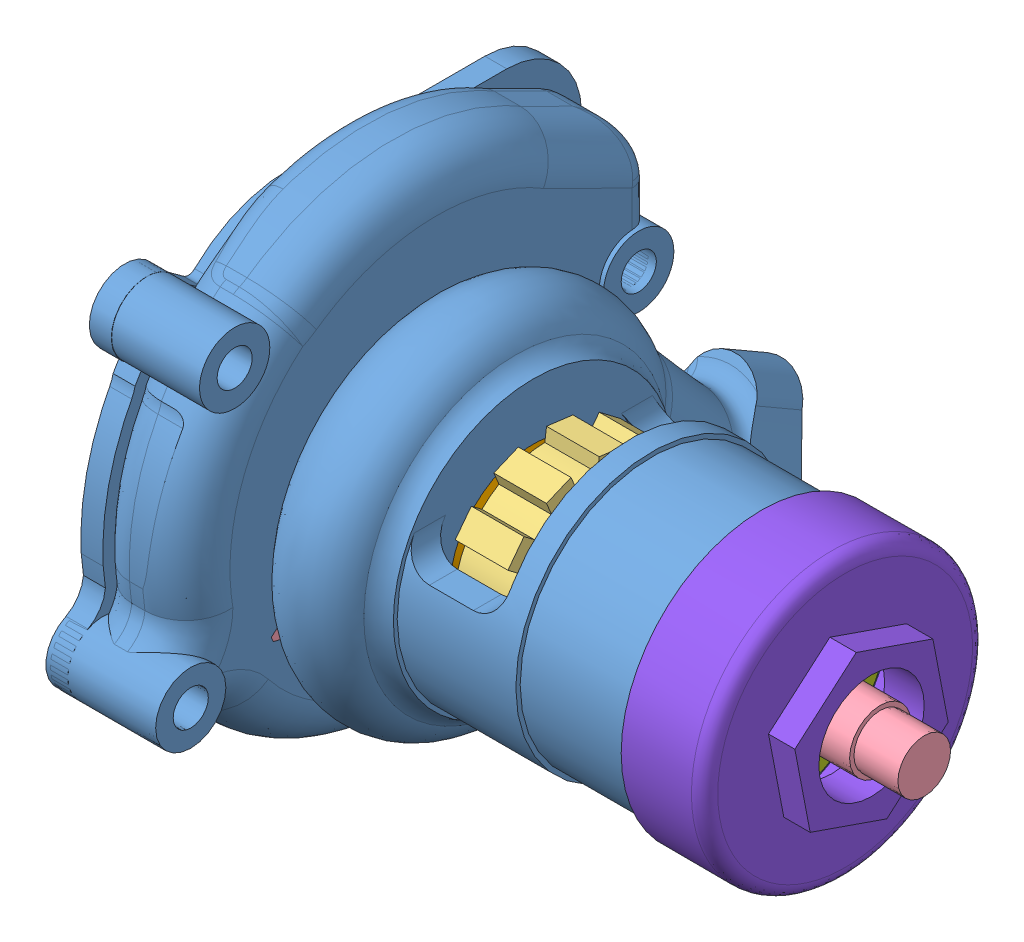
SolidWorks assembly Assem1, configuration Default. Lengths in mm.
Overall size (147 118.16 132.43).
10 component instances, 9 part files, 15 mates.
Components (placement in the parent):
- Part1Body-1: Part1Body [Default<As Machined>] at (7.1717 156.7959 111.416) size (101 118.16 132.43)
- Part3-1: Part3 [Default] at (15.1717 156.7959 111.416) x (0 0 1) z (-1 0 0) size (28 28 10)
- Assem2^Assem1-1: Assem2^Assem1 [Default] at (7.1717 156.7959 111.416) size (16 48 48) (virtual)
  - Part4-1: Part4 [Default] at origin size (16 48 48)
- Part5-1: Part5 [Default] at (-34.8283 156.7959 111.416) x (0 0 -1) z (1 0 0) size (75 75 147)
- Part6-1: Part6 [Default] at (28.6921 156.7959 111.416) size (3 42.38 42.38)
- Part7-1: Part7 [Default] at (35.3148 156.7959 111.416) x (0 0.24354 -0.969891) z (1 0 0) size (19 19 12)
- Part8-1: Part8 [Default] at (44.3792 156.7959 111.416) x (-1 0 0) z (0 0 1) size (23 54 54)
- Part9-1: Part9 [Default] at (56.1717 156.7959 111.416) size (25 64 64)
- PUMP_part 2-1: PUMP_part 2 [Default] at (-7.8283 156.7959 111.416) x (1 0 0) z (0 0.978148 -0.207912) size (54 42 42)
Mates (geometry in assembly coordinates):
- Concentric1: concentric anti-aligned: cylinder of Part3-1 through (5.1717 156.7959 111.416) axis (1 0 0) radius 14; circle of PUMP_part 2-1
- Coincident1: coincident anti-aligned: plane of Part3-1 through (5.1717 156.7959 111.416) normal (-1 0 0); plane of PUMP_part 2-1 through (5.1717 153.8851 97.722) normal (1 0 0)
- Concentric4: concentric anti-aligned: circle of Part6-1; cylinder of Part7-1 through (47.3148 156.7959 111.416) axis (-1 0 0) radius 9.5
- Concentric5: concentric anti-aligned: cylinder of Part5-1 through (61.1717 156.7959 111.416) axis (-1 0 0) radius 8; circle of Part6-1
- Coincident5: coincident anti-aligned: plane of Part5-1 through (33.1717 156.7959 111.416) normal (1 0 0); plane of Part6-1 through (33.1717 156.7959 111.416) normal (-1 0 0)
- Concentric7: concentric anti-aligned: circle of Part7-1; cylinder of Part8-1 through (35.1717 156.7959 111.416) axis (-1 0 0) radius 10
- Coincident6: coincident anti-aligned: plane of Part6-1 through (35.1717 156.7959 111.416) normal (1 0 0); plane of Part8-1 through (35.1717 146.7959 111.416) normal (-1 0 0)
- Concentric8: concentric aligned: circle of Assem2^Assem1-1/Part4-1; cylinder of PUMP_part 2-1 through (-34.8283 156.7959 111.416) axis (-1 0 0) radius 17.5
- Coincident7: coincident anti-aligned: plane of Assem2^Assem1-1/Part4-1 through (19.1717 156.7959 111.416) normal (-1 0 0); plane of PUMP_part 2-1 through (19.1717 153.1574 94.2984) normal (1 0 0)
- Concentric12: concentric aligned: cylinder of Part5-1 through (33.1717 156.7959 111.416) axis (-1 0 0) radius 9.5; cylinder of PUMP_part 2-1 through (-34.8283 156.7959 111.416) axis (-1 0 0) radius 10
- Coincident8: coincident anti-aligned: plane of Part5-1 through (-34.8283 156.7959 111.416) normal (1 0 0); plane of PUMP_part 2-1 through (-34.8283 154.7168 101.6345) normal (-1 0 0)
- Concentric13: concentric aligned: circle of Part1Body-1; cylinder of Part8-1 through (35.1717 156.7959 111.416) axis (-1 0 0) radius 25
- Coincident9: coincident anti-aligned: plane of Part1Body-1 through (56.1717 186.7959 111.416) normal (1 0 0); plane of Part8-1 through (56.1717 129.7959 111.416) normal (-1 0 0)
- Coincident10: coincident anti-aligned: plane of Part1Body-1 through (56.1717 186.7959 111.416) normal (1 0 0); plane of Part9-1 through (56.1717 156.7959 111.416) normal (-1 0 0)
- Concentric14: concentric anti-aligned: circle of Part1Body-1; circle of Part9-1
